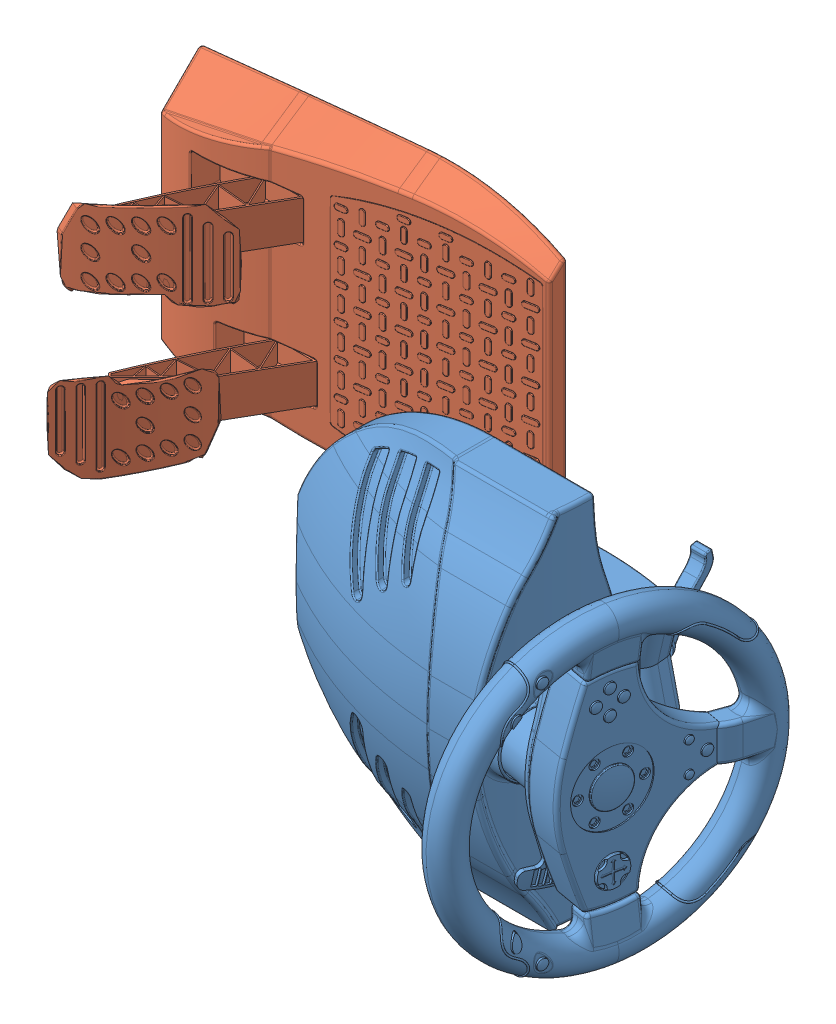
SolidWorks assembly Thrustmaster Ferrari Red Legend, configuration Default. Lengths in mm.
Overall size (508.84 398.26 295.45).
3 component instances, 2 part files, 0 mates.
Components (placement in the parent):
- Thrustmaster Ferrari Red Legend.stp-1: Thrustmaster Ferrari Red Legend.stp [Default] at origin size (508.84 398.26 295.45)
  - steering top.stp-1: steering top.stp [Default] at origin size (324.94 301.47 295.45)
  - Pedals.stp-1: Pedals.stp [Default] at (-169.1881 128.7516 349.0865) size (304.7 237.8 210.88)
